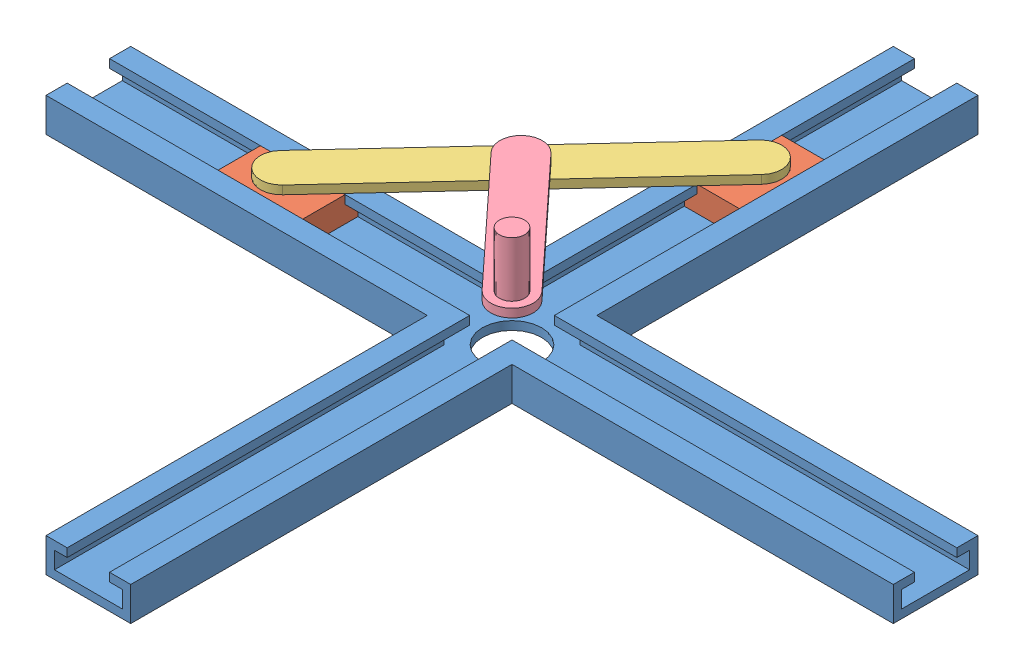
SolidWorks assembly 椭圆规, configuration 默认. Lengths in mm.
Overall size (200 26 200).
5 component instances, 4 part files, 10 mates.
Components (placement in the parent):
- 槽-1: 槽 [默认] at (-54.4255 -14.4878 26.2506) size (200 8 200)
- 塞-1: 塞 [默认] at (-98.8164 -10.4878 126.2506) x (0 0 1) z (0 -1 0) size (16 20 6)
- 塞-2: 塞 [默认] at (-54.4255 -10.4878 57.5852) x (1 0 0) z (0 -1 0) size (16 20 6)
- 连杆-1: 连杆 [默认] at (-64.6238 -3.4878 78.5849) x (0.679886 0 -0.733318) z (-0.733318 0 -0.679886) size (90 9 10)
- 零件4-2: 零件4 [默认] at (-64.6238 -3.4878 115.2508) x (0.679886 0 0.733318) z (0 1 0) size (50 10 17)
Mates (geometry in assembly coordinates):
- 同心1: concentric: cylinder of 塞-1 through (66.6097 -22.6022 100) axis (0 1 0) radius 2; cylinder of 连杆-1 through (66.6097 -8.6022 100) axis (0 1 0) radius 2
- 重合2: coincident: plane of 槽-1 through (-13.3579 -8.6022 200) normal (0 1 0); plane of 塞-1 through (56.6097 -8.6022 92) normal (0 -1 0)
- 重合3: coincident: plane of 槽-1 through (86.6421 -8.6022 92) normal (0 0 1); plane of 塞-1 through (56.6097 -4.6022 92) normal (0 0 -1)
- 重合5: coincident: plane of 槽-1 through (-5.3579 -8.6022 200) normal (-1 0 0); plane of 塞-2 through (-5.3579 -4.6022 107.7236) normal (1 0 0)
- 同心2: concentric: cylinder of 塞-2 through (-13.3579 -22.6022 97.7236) axis (0 1 0) radius 2; cylinder of 连杆-1 through (-13.3579 -8.6022 97.7236) axis (0 1 0) radius 2
- 重合6: coincident: plane of 塞-2 through (-21.3579 -8.6022 107.7236) normal (0 -1 0); plane of 连杆-1 through (97.1731 -8.6022 100.87) normal (0 -1 0)
- 重合7: coincident: plane of 塞-1 through (56.6097 -8.6022 92) normal (0 -1 0); plane of 连杆-1 through (97.1731 -8.6022 100.87) normal (0 -1 0)
- 同心4: concentric: cylinder of 连杆-1 through (26.6259 -9.6022 98.8618) axis (0 1 0) radius 2; cylinder of 零件4-2 through (26.6259 -1.6022 98.8618) axis (0 1 0) radius 2
- 重合15: coincident: plane of 连杆-1 through (66.6097 0.3978 100) normal (0 1 0); plane of 零件4-2 through (26.6259 0.3978 98.8618) normal (0 -1 0)
- 同心5: concentric: circle of 槽-1; circle of 零件4-2
